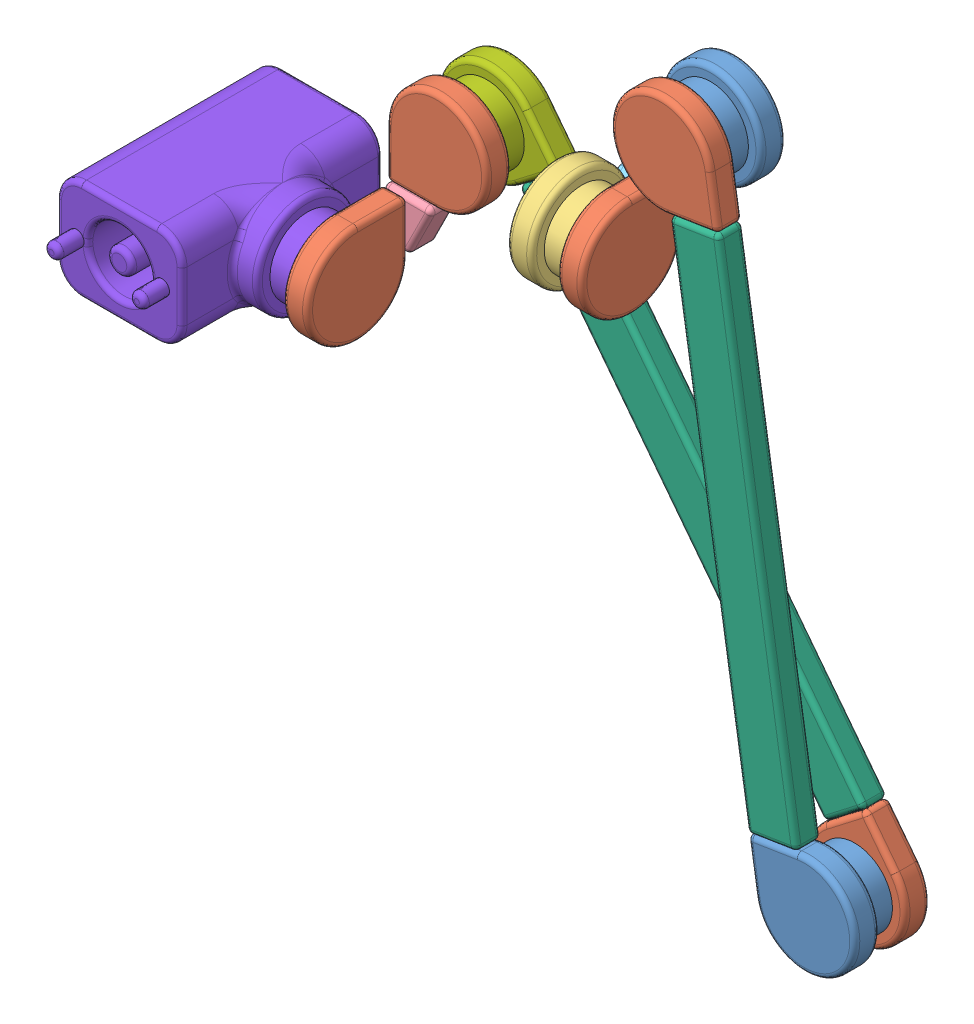
SolidWorks assembly ropy-arm-v1, configuration Défaut. Lengths in mm.
Overall size (1323.31 1424.21 506.54).
15 component instances, 8 part files, 41 mates.
Components (placement in the parent):
- ropy-arm-joint-03-2: ropy-arm-joint-03 [Défaut] at (200 300 -56.5363) x (1 0 0) z (0 0 -1) size (200 200 100)
- ropy-arm-joint-02-1: ropy-arm-joint-02 [Défaut] at (200 300 93.4637) x (-0.98765 -0.156674 0) z (0 0 1) size (200 200 100)
- ropy-arm-joint-02-2: ropy-arm-joint-02 [Défaut] at (150 100 100) x (0 -1 0) z (1 0 0) size (200 200 100)
- ropy-arm-joint-04-1: ropy-arm-joint-04 [Défaut] at (0 100 100) x (0 1 0) z (-1 0 0) size (200 200 100)
- ropy-arm-part-01-1: ropy-arm-part-01 [Défaut] at (100 169.2292 0) size (93.82 100 56.54)
- ropy-arm-part-02-1: ropy-arm-part-02 [Défaut] at (28.2934 -54.2372 0) x (1 0 0) z (0 0 -1) size (77.83 127.83 50)
- ropy-arm-part-03-1: ropy-arm-part-03 [Défaut] at (289.771 212.9902 65.1702) x (0 0 -1) z (0.156674 -0.98765 0) size (50 100 1000)
- ropy-arm-joint-03-3: ropy-arm-joint-03 [Défaut] at (486.7732 -869.5132 93.4637) x (0.98765 0.156674 0) z (0 0 1) size (200 200 100)
- ropy-arm-joint-02-3: ropy-arm-joint-02 [Défaut] at (486.7732 -869.5132 -56.5363) x (-0.791724 -0.610879 0) z (0 0 -1) size (200 200 100)
- ropy-arm-part-03-2: ropy-arm-part-03 [Défaut] at (485.0886 -744.5064 -28.2429) x (0 0 1) z (-0.610879 0.791724 0) size (50 100 1000)
- ropy-arm-joint-02-4: ropy-arm-joint-02 [Défaut] at (-246.2814 80.5557 93.4637) x (0 1 0) z (0 0 1) size (200 200 100)
- ropy-arm-joint-01-5: ropy-arm-joint-01 [Défaut] at (-246.2814 80.5557 -6.5363) x (-0.791724 -0.610879 0) z (0 0 1) size (200 200 100)
- ropy-arm-part-01-2: ropy-arm-part-01 [Défaut] at (-346.2814 -50.2151 100) size (93.82 100 56.54)
- ropy-arm-joint-02-5: ropy-arm-joint-02 [Défaut] at (-296.2814 -119.4443 200) x (0 -1 0) z (1 0 0) size (200 200 100)
- ropy-arm-head-1: ropy-arm-head [Défaut] at (-396.2814 -119.4443 200) x (0 0 1) z (1 0 0) size (450 215.66 350)
Mates (geometry in assembly coordinates):
- Coaxiale1: concentric anti-aligned: cylinder of ropy-arm-joint-03-2 through (200 300 43.4637) axis (0 0 -1) radius 50; cylinder of ropy-arm-joint-02-1 through (200 300 -6.5363) axis (0 0 1) radius 50
- Coïncidente3: coincident anti-aligned: plane of ropy-arm-joint-03-2 through (200 300 -6.5363) normal (0 0 1); plane of ropy-arm-joint-02-1 through (200 300 -6.5363) normal (0 0 -1)
- Coaxiale2: concentric anti-aligned: cylinder of ropy-arm-joint-02-2 through (50 100 100) axis (1 0 0) radius 50; cylinder of ropy-01-1 through (100 100 100) axis (-1 0 0) radius 50
- Coïncidente9: coincident anti-aligned: plane of ropy-arm-joint-02-2 through (50 100 100) normal (-1 0 0); plane of ropy-01-1 through (50 100 100) normal (1 0 0)
- Parallèle1: parallel anti-aligned: plane of ropy-01-1 through (50 0 0) normal (0 0 -1)
- Coïncidente13: coincident anti-aligned: plane of ropy-01-1 through (50 0 0) normal (0 0 -1)
- Coïncidente14: coincident anti-aligned: plane of ropy-01-1 through (0 100 100) normal (-1 0 0)
- Coïncidente20: coincident anti-aligned: plane of ropy-arm-joint-03-2 through (100 200 -6.5363) normal (0 -1 0); plane of ropy-arm-part-01-1 through (200 200 -197.9577) normal (0 1 0)
- Coïncidente22: coincident anti-aligned: plane of ropy-arm-joint-02-2 through (100 200 0) normal (0 0 -1); plane of ropy-arm-part-01-1 through (100 169.2292 0) normal (0 0 1)
- Coïncidente26: coincident anti-aligned: plane of ropy-01-1 through (50 0 0) normal (0 0 -1); plane of ropy-arm-part-02-1 through (28.2934 -54.2372 0) normal (0 0 1)
- Coïncidente30: coincident aligned: plane of ropy-arm-joint-02-1 through (298.765 315.6674 43.4637) normal (0.98765 0.156674 0); plane of ropy-arm-part-03-1 through (471.1059 -770.7481 93.4637) normal (0.98765 0.156674 0)
- Coïncidente33: coincident anti-aligned: plane of ropy-arm-joint-02-1 through (314.4324 216.9023 43.4637) normal (0.156674 -0.98765 0); plane of ropy-arm-part-03-1 through (289.771 212.9902 65.1702) normal (-0.156674 0.98765 0)
- Coïncidente34: coincident aligned: plane of ropy-arm-joint-02-1 through (200 300 93.4637) normal (0 0 1); plane of ropy-arm-part-03-1 through (471.1059 -770.7481 93.4637) normal (0 0 1)
- Coïncidente35: coincident anti-aligned: plane of ropy-arm-part-03-1 through (446.4445 -774.6602 65.1702) normal (0.156674 -0.98765 0); plane of ropy-arm-joint-03-3 through (372.3409 -786.4155 43.4637) normal (-0.156674 0.98765 0)
- Coïncidente36: coincident aligned: plane of ropy-arm-part-03-1 through (372.3409 -786.4155 93.4637) normal (-0.98765 -0.156674 0); plane of ropy-arm-joint-03-3 through (388.0082 -885.1805 43.4637) normal (-0.98765 -0.156674 0)
- Coïncidente37: coincident aligned: plane of ropy-arm-part-03-1 through (471.1059 -770.7481 93.4637) normal (0 0 1); plane of ropy-arm-joint-03-3 through (486.7732 -869.5132 93.4637) normal (0 0 1)
- Coaxiale3: concentric anti-aligned: cylinder of ropy-arm-joint-03-3 through (486.7732 -869.5132 -6.5363) axis (0 0 1) radius 50; cylinder of ropy-arm-joint-02-3 through (486.7732 -869.5132 43.4637) axis (0 0 -1) radius 50
- Coïncidente38: coincident anti-aligned: plane of ropy-arm-joint-03-3 through (486.7732 -869.5132 43.4637) normal (0 0 -1); plane of ropy-arm-joint-02-3 through (486.7732 -869.5132 43.4637) normal (0 0 1)
- Coïncidente39: coincident anti-aligned: plane of ropy-arm-joint-02-3 through (504.8578 -729.2529 -6.5363) normal (-0.610879 0.791724 0); plane of ropy-arm-part-03-2 through (485.0886 -744.5064 -28.2429) normal (0.610879 -0.791724 0)
- Coïncidente40: coincident aligned: plane of ropy-arm-joint-02-3 through (565.9457 -808.4253 -6.5363) normal (0.791724 0.610879 0); plane of ropy-arm-part-03-2 through (-106.0211 62.4712 -56.5363) normal (0.791724 0.610879 0)
- Coïncidente41: coincident aligned: plane of ropy-arm-joint-02-3 through (486.7732 -869.5132 -56.5363) normal (0 0 -1); plane of ropy-arm-part-03-2 through (-106.0211 62.4712 -56.5363) normal (0 0 -1)
- Coïncidente52: coincident anti-aligned: plane of ropy-arm-part-03-2 through (-125.7903 47.2177 -28.2429) normal (-0.610879 0.791724 0); plane of ropy-arm-joint-01-5 through (-106.0211 62.4712 -56.5363) normal (0.610879 -0.791724 0)
- Coïncidente53: coincident aligned: plane of ropy-arm-part-03-2 through (-106.0211 62.4712 -56.5363) normal (0.791724 0.610879 0); plane of ropy-arm-joint-01-5 through (-167.109 141.6436 -56.5363) normal (0.791724 0.610879 0)
- Coïncidente54: coincident aligned: plane of ropy-arm-part-03-2 through (-106.0211 62.4712 -56.5363) normal (0 0 -1); plane of ropy-arm-joint-01-5 through (-246.2814 80.5557 -56.5363) normal (0 0 -1)
- Coaxiale4: concentric anti-aligned: cylinder of ropy-arm-joint-02-4 through (-246.2814 80.5557 -6.5363) axis (0 0 1) radius 50; cylinder of ropy-arm-joint-01-5 through (-246.2814 80.5557 43.4637) axis (0 0 -1) radius 50
- Coïncidente55: coincident anti-aligned: plane of ropy-arm-joint-02-4 through (-246.2814 80.5557 -6.5363) normal (0 0 -1); plane of ropy-arm-joint-01-5 through (-246.2814 80.5557 -6.5363) normal (0 0 1)
- Parallèle4: parallel anti-aligned: plane of ropy-arm-joint-02-4 through (-346.2814 -19.4443 43.4637) normal (-1 0 0)
- Coïncidente57: coincident anti-aligned: plane of ropy-arm-joint-02-4 through (-246.2814 -19.4443 43.4637) normal (0 -1 0); plane of ropy-arm-part-01-2 through (-246.2814 -19.4443 -97.9577) normal (0 1 0)
- Coïncidente58: coincident aligned: plane of ropy-arm-joint-02-4 through (-346.2814 -19.4443 43.4637) normal (-1 0 0); plane of ropy-arm-part-01-2 through (-346.2814 -19.4443 -97.9577) normal (-1 0 0)
- Coïncidente59: coincident aligned: plane of ropy-arm-joint-02-4 through (-246.2814 80.5557 43.4637) normal (0 0 -1); plane of ropy-arm-part-01-2 through (-246.2814 80.5557 43.4637) normal (0 0 -1)
- Coïncidente60: coincident anti-aligned: plane of ropy-arm-part-01-2 through (-346.2814 -50.2151 100) normal (0 0 1); plane of ropy-arm-joint-02-5 through (-346.2814 -19.4443 100) normal (0 0 -1)
- Coïncidente63: coincident anti-aligned: plane of ropy-arm-joint-02-5 through (-396.2814 -119.4443 200) normal (-1 0 0); plane of ropy-arm-head-1 through (-396.2814 -119.4443 200) normal (1 0 0)
- Coïncidente64: coincident aligned: plane of ropy-arm-joint-02-2 through (100 200 100) normal (0 1 0); plane of ropy-arm-part-01-1 through (200 200 -197.9577) normal (0 1 0)
- Coïncidente66: coincident aligned: plane of ropy-arm-joint-02-2 through (100 100 100) normal (-1 0 0); plane of ropy-arm-part-01-1 through (100 200 -197.9577) normal (-1 0 0)
- Coïncidente67: coincident aligned: plane of ropy-arm-joint-03-2 through (100 300 -6.5363) normal (-1 0 0); plane of ropy-arm-part-01-1 through (100 200 -197.9577) normal (-1 0 0)
- Coïncidente68: coincident aligned: plane of ropy-arm-joint-03-2 through (200 300 -56.5363) normal (0 0 -1); plane of ropy-arm-part-01-1 through (200 300 -56.5363) normal (0 0 -1)
- Coïncidente69: coincident aligned: plane of ropy-arm-part-01-2 through (-346.2814 -19.4443 -97.9577) normal (-1 0 0); plane of ropy-arm-joint-02-5 through (-346.2814 -119.4443 200) normal (-1 0 0)
- Coïncidente70: coincident aligned: plane of ropy-arm-part-01-2 through (-246.2814 -19.4443 -97.9577) normal (0 1 0); plane of ropy-arm-joint-02-5 through (-346.2814 -19.4443 200) normal (0 1 0)
- Coaxiale6: concentric anti-aligned: cylinder of ropy-arm-joint-02-5 through (-396.2814 -119.4443 200) axis (1 0 0) radius 50; cylinder of ropy-arm-head-1 through (-346.2814 -119.4443 200) axis (-1 0 0) radius 50
- Parallèle5: parallel aligned: plane of ropy-arm-head-1 through (-396.2814 -119.4443 400) normal (0 0 1)
- Parallèle6: parallel aligned: plane of ropy-arm-part-02-1 through (28.2934 -54.2372 -50) normal (0 0 -1); plane of ropy-arm-part-03-2 through (-106.0211 62.4712 -56.5363) normal (0 0 -1)
